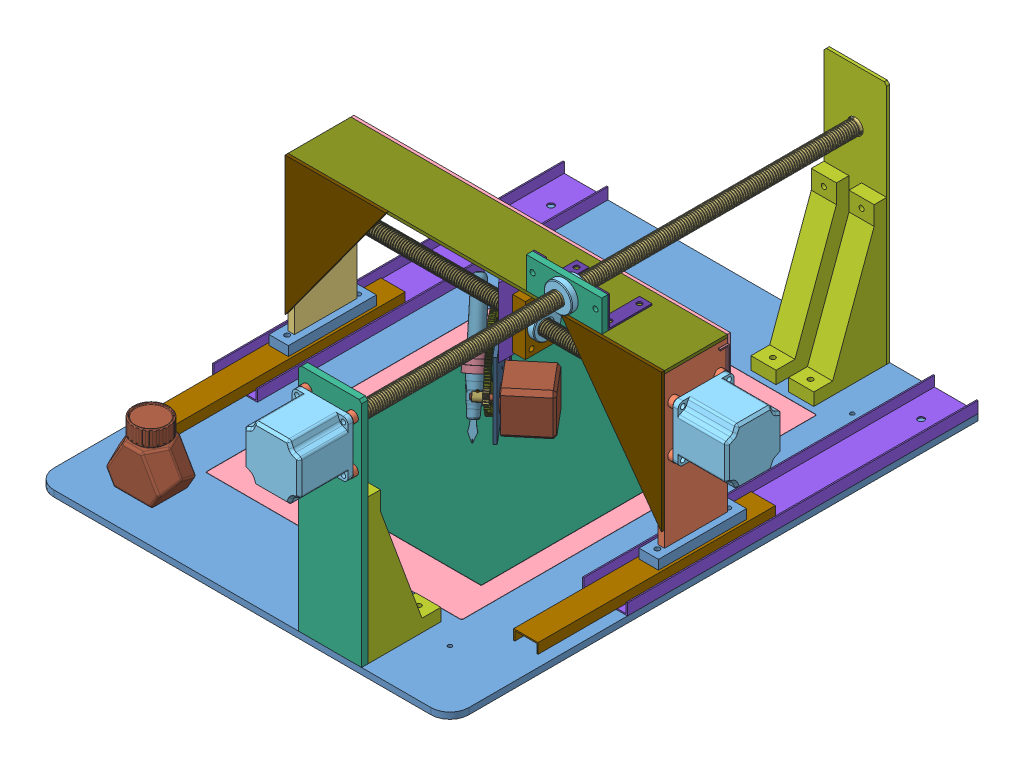
SolidWorks assembly Herald, configuration Default. Lengths in mm.
Overall size (459.08 262.99 592.84).
56 component instances, 36 part files, 131 mates.
Components (placement in the parent):
- Base-2: Base [Default] at (-178.3326 42.4149 224.7348) size (419.1 6.35 533.4)
- Stepper spacer-1: Stepper spacer [Default] at (96.4904 264.5125 229.8148) x (1 0 0) z (0 1 0) size (10.16 5.08 10.16)
- Stepper spacer-2: Stepper spacer [Default] at (143.2264 217.7765 229.8148) x (1 0 0) z (0 1 0) size (10.16 5.08 10.16)
- Stepper spacer-3: Stepper spacer [Default] at (143.2264 264.5125 229.8148) x (-0.279349 0.96019 0) z (-0.96019 -0.279349 0) size (10.16 5.08 10.16)
- Stepper spacer-6: Stepper spacer [Default] at (96.4904 217.7765 229.8148) x (1 0 0) z (0 1 0) size (10.16 5.08 10.16)
- Y axis threaded rod-1: Y axis threaded rod [Default] at (119.8584 241.1445 209.7488) x (0 0 -1) z (0.590642 -0.806934 0) size (518.41 15.92 15.92)
- Glass pane-3: Glass pane [Default] at (-98.1639 45.5649 -226.1152) x (0 0 1) z (-1 0 0) size (358.78 3.2 258.76)
- stepper motor_vexta PK266MA-2: stepper motor_vexta PK266MA [Default] at (226.391 199.6155 -15.0171) x (0 0 -1) z (1 0 0) size (56.39 56.39 74.42)
- Stepper spacer-7: Stepper spacer [Default] at (226.391 194.7895 -66.5791) x (0 1 0) z (0 0 1) size (10.16 5.08 10.16)
- Stepper spacer-8: Stepper spacer [Default] at (226.391 148.0535 -66.5791) x (0 1 0) z (0 0 1) size (10.16 5.08 10.16)
- Stepper spacer-9: Stepper spacer [Default] at (226.391 194.7895 -19.8431) x (0 1 0) z (0 0 1) size (10.16 5.08 10.16)
- Stepper spacer-10: Stepper spacer [Default] at (226.391 148.0535 -19.8431) x (0 1 0) z (0 0 1) size (10.16 5.08 10.16)
- Y axis stepper wall-3: Y axis stepper wall [Default] at (151.6084 48.7649 224.7348) x (-1 0 0) z (0 0 -1) size (63.5 233.27 6.35)
- Y axis stepper wall opposite-1: Y axis stepper wall opposite [Default] at (88.1084 48.7649 -308.6652) size (63.5 245.97 3.05)
- sldier_base-8: sldier_base [Default] at (-133.0698 60.2965 45.3473) x (-1 0 0) z (0 0 -1) size (45.26 11.53 354.01)
- slider_top-8: slider_top [Default] at (-143.3949 50.0349 125.3814) x (-1 0 0) z (0 0 -1) size (24.61 10.26 239.71)
- sldier_base-9: sldier_base [Default] at (240.7674 60.2965 45.3473) x (-1 0 0) z (0 0 -1) size (45.26 11.53 354.01)
- slider_top-9: slider_top [Default] at (230.4423 50.0349 125.3814) x (-1 0 0) z (0 0 -1) size (24.61 10.26 239.71)
- Rubber foot new-1: Rubber foot new [Default] at (177.2674 42.4149 -245.1652) x (-0.837169 0 -0.546944) z (-0.546944 0 0.837169) size (24.77 10.67 24.77)
- Rubber foot new-2: Rubber foot new [Default] at (-114.8326 42.4149 161.2348) x (-0.837169 0 -0.546944) z (-0.546944 0 0.837169) size (24.77 10.67 24.77)
- Rubber foot new-3: Rubber foot new [Default] at (177.2674 42.4149 161.2348) x (-0.837169 0 -0.546944) z (-0.546944 0 0.837169) size (24.77 10.67 24.77)
- Rubber foot new-4: Rubber foot new [Default] at (-114.8326 42.4149 -245.1652) x (-0.837169 0 -0.546944) z (-0.546944 0 0.837169) size (24.77 10.67 24.77)
- Ink bottle-1: Ink bottle [Default] at (-144.1882 48.7649 154.4245) size (62.44 62.79 38.1)
- X axis threaded rod-1: X axis threaded rod [Default] at (-155.5742 171.4215 -43.2111) x (1 0 0) z (0 0.602009 0.798489) size (361.9 15.92 15.92)
- x_sldier_base-1: x_sldier_base [Default] at (223.3049 217.4717 -65.9695) x (0 -1 0) z (-1 0 0) size (35.2 8.99 384.18)
- x_slider_top-1: x_slider_top [Default] at (59.6982 212.0107 -73.6911) x (0 -1 0) z (-1 0 0) size (24.28 7.29 231.78)
- Paper sheet-1: Paper sheet [Default] at (-75.6268 48.7649 92.6403) size (215.9 0.25 279.4)
- Recognizer top-1: Recognizer top [Default] at (221.311 225.2695 -11.4611) x (-1 0 0) z (0 -1 0) size (380.19 63.5 3.05)
- Recognizer top bracket-1: Recognizer top bracket [Default] at (157.9584 225.2695 -62.2611) x (0 0 1) z (-1 0 0) size (44.45 31.75 12.7)
- Recognizer top bracket-2: Recognizer top bracket [Default] at (94.4584 225.2695 -62.2611) x (0 0 1) z (-1 0 0) size (44.45 31.75 12.7)
- Recognizer bracket-1: Recognizer bracket [Default] at (-158.8762 85.5695 -11.4611) size (101.6 139.7 3.05)
- Recognizer bracket-2: Recognizer bracket [Default] at (221.311 85.5695 -8.4131) x (-1 0 0) z (0 0 -1) size (101.6 139.7 3.05)
- Recognizer foot-1: Recognizer foot [Default] at (-145.8968 60.2965 -87.6611) x (-1 0 0) z (0 0 -1) size (19.61 9.53 88.9)
- Recognizer foot-2: Recognizer foot [Default] at (227.9404 60.2965 -87.6611) x (-1 0 0) z (0 0 -1) size (19.61 9.53 88.9)
- Recognizer stepper arm-1: Recognizer stepper arm [Default] at (214.961 63.3445 -11.4611) x (0 0 -1) z (1 0 0) size (63.5 158.88 6.35)
- Recognizer regular arm-1: Recognizer regular arm [Default] at (-152.5262 63.3445 -74.9611) x (0 0 1) z (-1 0 0) size (63.5 158.88 6.35)
- Recognizer back plate-1: Recognizer back plate [Default] at (221.311 174.4695 -74.9611) x (-1 0 0) z (0 0 -1) size (380.19 50.8 3.05)
- ACME nut fast travel-1: ACME nut fast travel [Default] at (119.8584 241.1445 -5.1111) x (-1 0 0) z (0 -1 0) size (28.45 19.05 28.45)
- Recognizer nut plate-1: Recognizer nut plate [Default] at (157.9584 225.2695 -11.4611) x (-1 0 0) z (0 0 -1) size (76.2 31.75 6.35)
- Gusset-1: Gusset [Default] at (88.1084 48.7649 218.3848) size (25.4 146.05 73.66)
- Gusset-2: Gusset [Default] at (151.6084 48.7649 -305.6172) x (-1 0 0) z (0 0 -1) size (25.4 146.05 73.66)
- Gusset-4: Gusset [Default] at (126.2084 48.7649 218.3848) size (25.4 146.05 73.66)
- Gusset-5: Gusset [Default] at (113.5084 48.7649 -305.6172) x (-1 0 0) z (0 0 -1) size (25.4 146.05 73.66)
- stepper motor_vexta PK266MA-3: stepper motor_vexta PK266MA [Default] at (91.6644 269.3385 229.8148) size (56.39 56.39 74.42)
- L shape-3: L shape [Default] at (49.5883 143.9895 -15.6013) x (0 0 -1) z (1 0 0) size (50.8 69.85 42.63)
- Print head nut plate-2: Print head nut plate [Default] at (49.5883 171.4215 -46.4369) x (0 0 -1) z (1 0 0) size (33.02 50.8 12.7)
- ACME nut fast travel-3: ACME nut fast travel [Default] at (68.6383 171.4215 -46.4369) x (0 -0.167452 -0.98588) z (0 0.98588 -0.167452) size (28.45 19.05 28.45)
- Mechanical plate-2: Mechanical plate [Default] at (54.4149 80.4895 -4.9098) x (-0.642788 0 -0.766044) z (0.766044 0 -0.642788) size (88.9 76.2 3.17)
- Stepper Pololu-4: Stepper Pololu [Default] at (85.9354 124.2245 -37.6249) x (-0.642788 0 -0.766044) z (0 1 0) size (42.3 64 42.3)
- Gear small-2: Gear small [Default] at (32.4517 103.0745 -20.3561) x (-0.766044 0 0.642788) z (0.619672 0.265763 0.738496) size (12.72 12.73 12.52)
- P clamp-3: P clamp [Default] at (-11.0372 89.3708 -70.3427) x (-0.549529 -0.518768 -0.654903) z (-0.333457 0.854915 -0.397399) size (35.56 20.32 16.76)
- Pen-3: Pen [Default] at (-22.3687 147.4305 -68.0409) x (-0.333457 0.854915 -0.397399) z (-0.549529 -0.518768 -0.654903) size (122.97 14 14)
- Spacer large-1: Spacer large [Default] at (9.6686 103.0745 -58.2363) x (-0.492404 0.642788 -0.586824) z (0.413176 0.766044 0.492404) size (27.94 5.71 27.94)
- Gear large-2: Gear large [Default] at (4.3859 103.0745 -53.8036) x (0.766044 0 -0.642788) z (-0.549529 -0.518768 -0.654903) size (12.71 77.81 77.81)
- Gear back plate-1: Gear back plate [Default] at (14.6303 103.0745 -62.3997) x (0.549529 0.518768 0.654903) z (0.333457 -0.854915 0.397399) size (22.86 3.05 22.86)
- Set screw-1: Set screw [Default] at (26.7072 107.9333 -17.2844) x (0.383542 -0.125263 -0.914989) z (0.170829 -0.964039 0.203586) size (2.54 2.54 2.54)
Mates (geometry in assembly coordinates):
- Coincident59: coincident anti-aligned: plane of Base-2 through (-98.1639 45.5649 -226.1152) normal (1 0 0); plane of Glass pane-3 through (-98.1639 48.7649 131.5098) normal (-1 0 0)
- Coincident60: coincident anti-aligned: plane of Base-2 through (-98.1639 45.5649 132.6598) normal (0 0 -1); plane of Glass pane-3 through (159.4486 48.7649 132.6598) normal (0 0 1)
- Coincident61: coincident aligned: plane of Base-2 through (-178.3326 48.7649 224.7348) normal (0 1 0); plane of Glass pane-3 through (-98.1639 48.7649 -226.1152) normal (0 1 0)
- Concentric86: concentric anti-aligned: circle of stepper motor_vexta PK266MA-2; circle of Stepper spacer-7
- Concentric87: concentric anti-aligned: circle of stepper motor_vexta PK266MA-2; circle of Stepper spacer-10
- Coincident128: coincident anti-aligned: plane of stepper motor_vexta PK266MA-2 through (226.391 199.6155 -15.0171) normal (-1 0 0); plane of Stepper spacer-7 through (226.391 194.7895 -66.5791) normal (1 0 0)
- Concentric97: concentric aligned: circle of Stepper spacer-1; circle of Y axis stepper wall-3
- Concentric98: concentric aligned: circle of Stepper spacer-3; circle of Y axis stepper wall-3
- Concentric99: concentric aligned: circle of Stepper spacer-6; circle of Y axis stepper wall-3
- Concentric100: concentric aligned: circle of Stepper spacer-2; circle of Y axis stepper wall-3
- Coincident138: coincident anti-aligned: plane of Stepper spacer-2 through (143.2264 217.7765 224.7348) normal (0 0 -1); plane of Y axis stepper wall-3 through (151.6084 48.7649 224.7348) normal (0 0 1)
- Coincident139: coincident anti-aligned: plane of Stepper spacer-6 through (96.4904 217.7765 224.7348) normal (0 0 -1); plane of Y axis stepper wall-3 through (151.6084 48.7649 224.7348) normal (0 0 1)
- Coincident140: coincident anti-aligned: plane of Stepper spacer-3 through (143.2264 264.5125 224.7348) normal (0 0 -1); plane of Y axis stepper wall-3 through (151.6084 48.7649 224.7348) normal (0 0 1)
- Coincident141: coincident anti-aligned: plane of Stepper spacer-1 through (96.4904 264.5125 224.7348) normal (0 0 -1); plane of Y axis stepper wall-3 through (151.6084 48.7649 224.7348) normal (0 0 1)
- LimitDistance1: limit distance = 194.3341 mm aligned: plane of slider_top-8 through (-143.3949 50.0349 -114.3311) normal (0 0 -1); plane of sldier_base-8 through (-133.0698 60.2965 -308.6652) normal (0 0 -1)
- Coincident3: coincident aligned: plane of sldier_base-8 through (-155.7012 60.2965 45.3473) normal (-1 0 0); plane of slider_top-8 through (-155.7012 50.0349 125.3814) normal (-1 0 0)
- Coincident4: coincident anti-aligned: plane of sldier_base-8 through (-177.0626 50.0349 -308.6652) normal (0 1 0); plane of slider_top-8 through (-144.6649 50.0349 -114.3311) normal (0 -1 0)
- Coincident145: coincident anti-aligned: plane of Base-2 through (-178.3326 48.7649 224.7348) normal (0 1 0); plane of sldier_base-8 through (-133.0698 48.7649 -308.6652) normal (0 -1 0)
- Coincident147: coincident anti-aligned: plane of Base-2 through (-178.3326 42.4149 224.7348) normal (0 -1 0); plane of Rubber foot new-1 through (175.1941 42.4149 -246.5197) normal (0 1 0)
- Coincident148: coincident anti-aligned: plane of Base-2 through (-178.3326 42.4149 224.7348) normal (0 -1 0); plane of Rubber foot new-2 through (-116.9059 42.4149 159.8803) normal (0 1 0)
- Coincident149: coincident anti-aligned: plane of Base-2 through (-178.3326 42.4149 224.7348) normal (0 -1 0); plane of Rubber foot new-3 through (175.1941 42.4149 159.8803) normal (0 1 0)
- Coincident150: coincident anti-aligned: plane of Base-2 through (-178.3326 42.4149 224.7348) normal (0 -1 0); plane of Rubber foot new-4 through (-116.9059 42.4149 -246.5197) normal (0 1 0)
- Coincident151: coincident anti-aligned: plane of Base-2 through (-178.3326 48.7649 224.7348) normal (0 1 0); plane of Ink bottle-1 through (-93.3882 48.7649 192.5245) normal (0 -1 0)
- Coincident152: coincident anti-aligned: plane of stepper motor_vexta PK266MA-2 through (206.325 171.4215 -43.2111) normal (-1 0 0); plane of X axis threaded rod-1 through (206.325 171.4215 -43.2111) normal (1 0 0)
- Coincident155: coincident anti-aligned: plane of x_sldier_base-1 through (-160.8701 183.5373 -73.6911) normal (0 0 1); plane of x_slider_top-1 through (-172.0768 187.7283 -73.6911) normal (0 0 -1)
- Coincident156: coincident aligned: plane of x_sldier_base-1; plane of x_slider_top-1
- Coincident165: coincident anti-aligned: plane of Base-2 through (-178.3326 48.7649 224.7348) normal (0 1 0); plane of Paper sheet-1 through (-75.6268 48.7649 92.6403) normal (0 -1 0)
- LimitDistance2: limit distance = 163.6067 mm aligned: plane of x_slider_top-1 through (59.6982 212.0107 -73.6911) normal (1 0 0); plane of x_sldier_base-1 through (223.3049 217.4717 -65.9695) normal (1 0 0)
- Concentric145: concentric anti-aligned: circle of stepper motor_vexta PK266MA-2; circle of X axis threaded rod-1
- Coincident203: coincident aligned: plane of Base-2 through (-178.3326 48.7649 224.7348) normal (0 0 1); plane of Y axis stepper wall-3 through (151.6084 48.7649 224.7348) normal (0 0 1)
- Coincident204: coincident anti-aligned: plane of Base-2 through (-178.3326 48.7649 224.7348) normal (0 1 0); plane of Y axis stepper wall-3 through (151.6084 48.7649 218.3848) normal (0 -1 0)
- Coincident210: coincident aligned: plane of Base-2 through (-178.3326 48.7649 -308.6652) normal (0 0 -1); plane of Y axis stepper wall opposite-1 through (88.1084 48.7649 -308.6652) normal (0 0 -1)
- Coincident211: coincident anti-aligned: plane of Base-2 through (-178.3326 48.7649 224.7348) normal (0 1 0); plane of Y axis stepper wall opposite-1 through (88.1084 48.7649 -305.6172) normal (0 -1 0)
- Concentric172: concentric anti-aligned: circle of Y axis threaded rod-1; circle of Y axis stepper wall opposite-1
- Coincident7: coincident anti-aligned: plane of Recognizer top-1 through (221.311 225.2695 -11.4611) normal (0 1 0); plane of Recognizer top bracket-1 through (145.2584 225.2695 -62.2611) normal (0 -1 0)
- Coincident14: coincident anti-aligned: plane of Recognizer top-1 through (221.311 225.2695 -11.4611) normal (0 1 0); plane of Recognizer top bracket-2 through (81.7584 225.2695 -62.2611) normal (0 -1 0)
- Coincident26: coincident aligned: plane of Recognizer top-1 through (221.311 225.2695 -11.4611) normal (0 1 0); plane of Recognizer bracket-1 through (-158.8762 225.2695 -8.4131) normal (0 1 0)
- Coincident27: coincident anti-aligned: plane of Recognizer top-1 through (221.311 222.2215 -11.4611) normal (0 0 1); plane of Recognizer bracket-2 through (221.311 85.5695 -11.4611) normal (0 0 -1)
- Coincident29: coincident aligned: plane of Recognizer top-1 through (221.311 225.2695 -11.4611) normal (0 1 0); plane of Recognizer bracket-2 through (221.311 225.2695 -11.4611) normal (0 1 0)
- Coincident56: coincident anti-aligned: plane of Recognizer top-1 through (221.311 222.2215 -11.4611) normal (0 0 1); plane of Recognizer bracket-1 through (-158.8762 85.5695 -11.4611) normal (0 0 -1)
- Coincident57: coincident aligned: plane of Recognizer top-1 through (221.311 222.2215 -11.4611) normal (1 0 0); plane of Recognizer stepper arm-1 through (221.311 63.3445 -11.4611) normal (1 0 0)
- Coincident58: coincident anti-aligned: plane of Recognizer top-1 through (221.311 222.2215 -11.4611) normal (0 -1 0); plane of Recognizer stepper arm-1 through (221.311 222.2215 -11.4611) normal (0 1 0)
- Coincident215: coincident aligned: plane of Recognizer top-1 through (-158.8762 222.2215 -11.4611) normal (-1 0 0); plane of Recognizer regular arm-1 through (-158.8762 63.3445 -74.9611) normal (-1 0 0)
- Coincident63: coincident aligned: plane of Recognizer top-1 through (221.311 225.2695 -11.4611) normal (0 1 0); plane of Recognizer back plate-1 through (221.311 225.2695 -78.0091) normal (0 1 0)
- Coincident64: coincident anti-aligned: plane of Recognizer top-1 through (221.311 222.2215 -74.9611) normal (0 0 -1); plane of Recognizer back plate-1 through (221.311 174.4695 -74.9611) normal (0 0 1)
- Coincident65: coincident anti-aligned: plane of Recognizer top-1 through (221.311 222.2215 -11.4611) normal (0 -1 0); plane of Recognizer regular arm-1 through (-158.8762 222.2215 -74.9611) normal (0 1 0)
- Coincident80: coincident aligned: plane of Recognizer top-1 through (221.311 222.2215 -11.4611) normal (0 0 1); plane of Recognizer nut plate-1 through (157.9584 225.2695 -11.4611) normal (0 0 1)
- Concentric19: concentric aligned: circle of Recognizer top bracket-1; circle of Recognizer nut plate-1
- Coincident75: coincident anti-aligned: plane of Recognizer top bracket-1 through (145.2584 225.2695 -17.8111) normal (0 0 1); plane of Recognizer nut plate-1 through (157.9584 225.2695 -17.8111) normal (0 0 -1)
- Concentric18: concentric aligned: circle of Recognizer top bracket-2; circle of Recognizer nut plate-1
- Concentric21: concentric aligned: circle of Recognizer top bracket-2; circle of Recognizer nut plate-1
- Coincident78: coincident anti-aligned: plane of Recognizer top bracket-2 through (81.7584 225.2695 -17.8111) normal (0 0 1); plane of Recognizer nut plate-1 through (157.9584 225.2695 -17.8111) normal (0 0 -1)
- Coincident51: coincident aligned: plane of Recognizer bracket-1 through (-158.8762 85.5695 -8.4131) normal (-1 0 0); plane of Recognizer regular arm-1 through (-158.8762 63.3445 -74.9611) normal (-1 0 0)
- Coincident52: coincident anti-aligned: plane of Recognizer bracket-1 through (-158.8762 85.5695 -11.4611) normal (0 0 -1); plane of Recognizer regular arm-1 through (-158.8762 63.3445 -11.4611) normal (0 0 1)
- Coincident40: coincident anti-aligned: plane of Recognizer bracket-2 through (221.311 85.5695 -11.4611) normal (0 0 -1); plane of Recognizer stepper arm-1 through (221.311 63.3445 -11.4611) normal (0 0 1)
- Coincident216: coincident aligned: plane of Recognizer bracket-2 through (221.311 85.5695 -11.4611) normal (1 0 0); plane of Recognizer stepper arm-1 through (221.311 63.3445 -11.4611) normal (1 0 0)
- Coincident69: coincident anti-aligned: plane of Recognizer foot-1 through (-158.8762 63.3445 -12.7311) normal (1 0 0); plane of Recognizer regular arm-1 through (-158.8762 63.3445 -74.9611) normal (-1 0 0)
- Coincident68: coincident anti-aligned: plane of Recognizer foot-2 through (221.311 63.3445 -12.7311) normal (-1 0 0); plane of Recognizer stepper arm-1 through (221.311 63.3445 -11.4611) normal (1 0 0)
- Coincident62: coincident aligned: plane of Recognizer stepper arm-1 through (221.311 63.3445 -11.4611) normal (1 0 0); plane of Recognizer back plate-1 through (221.311 174.4695 -78.0091) normal (1 0 0)
- Concentric20: concentric anti-aligned: cylinder of ACME nut fast travel-1 through (119.8584 241.1445 -5.1111) axis (0 0 -1) radius 11.8999; cylinder of Recognizer nut plate-1 through (119.8584 241.1445 -17.8111) axis (0 0 1) radius 11.8999
- Coincident76: coincident anti-aligned: plane of ACME nut fast travel-1 through (105.6344 241.1445 -11.4611) normal (0 0 -1); plane of Recognizer nut plate-1 through (157.9584 225.2695 -11.4611) normal (0 0 1)
- Coincident217: coincident anti-aligned: plane of Recognizer foot-1 through (-145.8968 60.2965 -87.6611) normal (0 -1 0); plane of slider_top-8 through (-143.3949 60.2965 -114.3311) normal (0 1 0)
- Coincident218: coincident anti-aligned: plane of Recognizer stepper arm-1 through (221.311 63.3445 -11.4611) normal (1 0 0); plane of Stepper spacer-7 through (221.311 194.7895 -66.5791) normal (-1 0 0)
- Coincident219: coincident anti-aligned: plane of Recognizer stepper arm-1 through (221.311 63.3445 -11.4611) normal (1 0 0); plane of Stepper spacer-10 through (221.311 148.0535 -19.8431) normal (-1 0 0)
- Coincident220: coincident anti-aligned: plane of Recognizer stepper arm-1 through (221.311 63.3445 -11.4611) normal (1 0 0); plane of Stepper spacer-8 through (221.311 148.0535 -66.5791) normal (-1 0 0)
- Coincident221: coincident anti-aligned: plane of Recognizer stepper arm-1 through (221.311 63.3445 -11.4611) normal (1 0 0); plane of Stepper spacer-9 through (221.311 194.7895 -19.8431) normal (-1 0 0)
- Concentric176: concentric anti-aligned: circle of Recognizer stepper arm-1; circle of Stepper spacer-10
- Concentric177: concentric anti-aligned: circle of Recognizer stepper arm-1; circle of Stepper spacer-8
- Concentric178: concentric anti-aligned: circle of Recognizer stepper arm-1; circle of Stepper spacer-9
- Concentric179: concentric anti-aligned: circle of Recognizer stepper arm-1; circle of Stepper spacer-7
- Coincident222: coincident anti-aligned: plane of Recognizer back plate-1 through (221.311 174.4695 -74.9611) normal (0 0 1); plane of x_sldier_base-1 through (-160.8701 217.4717 -74.9611) normal (0 0 -1)
- Concentric180: concentric aligned: circle of Recognizer back plate-1; circle of x_sldier_base-1
- Concentric181: concentric aligned: circle of Recognizer back plate-1; circle of x_sldier_base-1
- Coincident223: coincident anti-aligned: plane of Y axis stepper wall-3 through (151.6084 48.7649 218.3848) normal (0 0 -1); plane of Gusset-4 through (151.6084 48.7649 218.3848) normal (0 0 1)
- Coincident224: coincident aligned: plane of Y axis stepper wall-3 through (151.6084 48.7649 218.3848) normal (1 0 0); plane of Gusset-4 through (151.6084 48.7649 218.3848) normal (1 0 0)
- Coincident225: coincident anti-aligned: plane of Base-2 through (-178.3326 48.7649 224.7348) normal (0 1 0); plane of Gusset-4 through (151.6084 48.7649 144.7248) normal (0 -1 0)
- Coincident229: coincident anti-aligned: plane of Base-2 through (-178.3326 48.7649 224.7348) normal (0 1 0); plane of Gusset-1 through (113.5084 48.7649 144.7248) normal (0 -1 0)
- Coincident230: coincident anti-aligned: plane of Y axis stepper wall-3 through (151.6084 48.7649 218.3848) normal (0 0 -1); plane of Gusset-1 through (113.5084 48.7649 218.3848) normal (0 0 1)
- Coincident231: coincident aligned: plane of Y axis stepper wall-3 through (88.1084 48.7649 218.3848) normal (-1 0 0); plane of Gusset-1 through (88.1084 48.7649 218.3848) normal (-1 0 0)
- Coincident232: coincident anti-aligned: plane of Y axis stepper wall opposite-1 through (88.1084 48.7649 -305.6172) normal (0 0 1); plane of Gusset-5 through (88.1084 48.7649 -305.6172) normal (0 0 -1)
- Coincident233: coincident anti-aligned: plane of Base-2 through (-178.3326 48.7649 224.7348) normal (0 1 0); plane of Gusset-5 through (88.1084 48.7649 -231.9572) normal (0 -1 0)
- Coincident234: coincident aligned: plane of Y axis stepper wall opposite-1 through (88.1084 48.7649 -305.6172) normal (-1 0 0); plane of Gusset-5 through (88.1084 48.7649 -305.6172) normal (-1 0 0)
- Coincident235: coincident anti-aligned: plane of Base-2 through (-178.3326 48.7649 224.7348) normal (0 1 0); plane of Gusset-2 through (126.2084 48.7649 -231.9572) normal (0 -1 0)
- Coincident236: coincident anti-aligned: plane of Y axis stepper wall opposite-1 through (88.1084 48.7649 -305.6172) normal (0 0 1); plane of Gusset-2 through (126.2084 48.7649 -305.6172) normal (0 0 -1)
- Coincident237: coincident aligned: plane of Y axis stepper wall opposite-1 through (151.6084 48.7649 -305.6172) normal (1 0 0); plane of Gusset-2 through (151.6084 48.7649 -305.6172) normal (1 0 0)
- Concentric183: concentric aligned: circle of slider_top-8; circle of Recognizer foot-1
- Coincident239: coincident anti-aligned: plane of Recognizer foot-2 through (227.9404 63.3445 -87.6611) normal (0 1 0); plane of Recognizer stepper arm-1 through (221.311 63.3445 -11.4611) normal (0 -1 0)
- Coincident240: coincident anti-aligned: plane of slider_top-9 through (230.4423 60.2965 -114.3311) normal (0 1 0); plane of Recognizer foot-2 through (227.9404 60.2965 -87.6611) normal (0 -1 0)
- Concentric184: concentric aligned: circle of slider_top-9; circle of Recognizer foot-2
- Coincident241: coincident anti-aligned: plane of Stepper spacer-2 through (143.2264 217.7765 229.8148) normal (0 0 1); plane of stepper motor_vexta PK266MA-3 through (91.6644 269.3385 229.8148) normal (0 0 -1)
- Concentric185: concentric anti-aligned: circle of Y axis stepper wall-3; circle of stepper motor_vexta PK266MA-3
- Concentric186: concentric aligned: circle of Stepper spacer-1; circle of stepper motor_vexta PK266MA-3
- Concentric187: concentric aligned: circle of Y axis threaded rod-1; circle of stepper motor_vexta PK266MA-3
- Concentric189: concentric anti-aligned: cylinder of Y axis threaded rod-1 through (119.8584 241.1445 -308.6652) axis (0 0 1) radius 6.35; cylinder of ACME nut fast travel-1 through (119.8584 241.1445 -5.1111) axis (0 0 -1) radius 14.224
- Coincident242: coincident anti-aligned: plane of Recognizer foot-2 through (221.311 63.3445 -12.7311) normal (0 0 -1); plane of Recognizer stepper arm-1 through (214.961 63.3445 -12.7311) normal (0 0 1)
- Concentric190: concentric anti-aligned: circle of Base-2; circle of Rubber foot new-2
- Concentric191: concentric anti-aligned: circle of Base-2; circle of Rubber foot new-3
- Concentric192: concentric aligned: cylinder of Base-2 through (177.2674 48.7649 -245.1652) axis (0 1 0) radius 2.0193; circle of Rubber foot new-1
- Concentric193: concentric anti-aligned: circle of Base-2; circle of Rubber foot new-4
- Coincident243: coincident aligned: plane of Base-2 through (-178.3326 48.7649 -308.6652) normal (0 0 -1); plane of sldier_base-8 through (-133.0698 60.2965 -308.6652) normal (0 0 -1)
- Concentric1: concentric aligned: cylinder of L shape-3 through (49.5883 190.4715 -36.2769) axis (-1 0 0) radius 2.3559; cylinder of Print head nut plate-2 through (62.2883 190.4715 -36.2769) axis (-1 0 0) radius 2.54
- Concentric2: concentric aligned: cylinder of L shape-3 through (49.5883 190.4715 -56.5969) axis (-1 0 0) radius 2.3559; cylinder of Print head nut plate-2 through (62.2883 190.4715 -56.5969) axis (-1 0 0) radius 2.54
- Concentric3: concentric: cylinder of Print head nut plate-2 through (62.2883 171.4215 -46.4369) axis (-1 0 0) radius 11.8999; cylinder of ACME nut fast travel-3 through (16.413 171.4215 -46.4369) axis (-1 0 0) radius 11.8999
- Concentric4: concentric aligned: circle of Mechanical plate-2; circle of Stepper Pololu-4
- Concentric5: concentric aligned: cylinder of Mechanical plate-2 through (30.1937 87.5595 -38.7149) axis (-0.766044 0 0.642788) radius 1.4605; cylinder of Stepper Pololu-4 through (35.556 87.5595 -43.2144) axis (-0.766044 0 0.642788) radius 1.5
- Coincident245: coincident anti-aligned: plane of Mechanical plate-2 through (56.8471 80.4895 -6.9506) normal (0.766044 0 -0.642788); plane of Stepper Pololu-4 through (33.0959 103.0745 -35.2562) normal (-0.766044 0 0.642788)
- Coincident19: coincident anti-aligned: plane of Mechanical plate-2 through (54.4149 80.4895 -4.9098) normal (-0.766044 0 0.642788); plane of Spacer large-1 through (9.6686 103.0745 -58.2363) normal (0.766044 0 -0.642788)
- Concentric13: concentric anti-aligned: cylinder of Mechanical plate-2 through (12.1008 103.0745 -60.2772) axis (-0.766044 0 0.642788) radius 10.3124; cylinder of Spacer large-1 through (5.2926 103.0745 -54.5644) axis (0.766044 0 -0.642788) radius 10.3124
- Concentric7: concentric aligned: circle of Stepper Pololu-4; circle of Gear small-2
- Tangent1: tangent anti-aligned: cylinder of Stepper Pololu-4 through (23.3136 103.0745 -12.6883) axis (-0.766044 0 0.642788) radius 2.5; plane of Set screw-1 through (27.1411 105.4846 -16.7673) normal (0.170829 -0.964039 0.203586)
- GearMate2: gear = 12.3031 : 77.3906 mm: circle of Gear large-2; circle of Gear small-2
- Concentric196: concentric anti-aligned: cylinder of Gear small-2 through (26.4811 109.2093 -17.5539) axis (0.170829 -0.964039 0.203586) radius 1.27; cylinder of Set screw-1 through (27.1411 105.4846 -16.7673) axis (-0.170829 0.964039 -0.203586) radius 1.27
- Concentric12: concentric anti-aligned: circle of P clamp-3; circle of Pen-3
- Coincident18: coincident aligned: plane of P clamp-3 through (-11.0372 89.3708 -70.3427) normal (-0.333457 0.854915 -0.397399); plane of Pen-3
- Parallel2: parallel anti-aligned: plane of P clamp-3; plane of Pen-3 through (17.7323 52.8421 -25.96) normal (0.549529 0.518768 0.654903)
- Coincident24: coincident aligned: circle of P clamp-3; circle of Gear large-2
- Concentric15: concentric aligned: cylinder of P clamp-3 through (-3.4999 96.4862 -61.36) axis (-0.766044 0 0.642788) radius 1.27; cylinder of Gear large-2 through (5.3163 96.4862 -68.7577) axis (-0.766044 0 0.642788) radius 1.27
- Concentric14: concentric anti-aligned: cylinder of Spacer large-1 through (5.2926 103.0745 -54.5644) axis (0.766044 0 -0.642788) radius 13.97; circle of Gear large-2
- Coincident23: coincident anti-aligned: plane of Spacer large-1 through (5.2926 103.0745 -54.5644) normal (-0.766044 0 0.642788); plane of Gear large-2 through (5.2926 103.0745 -54.5644) normal (0.766044 0 -0.642788)
- Coincident247: coincident anti-aligned: cylinder of Gear large-2 through (7.969 109.178 -61.6449) axis (0.766044 0 -0.642788) radius 1.27; circle of Gear back plate-1
- Concentric17: concentric aligned: cylinder of Gear large-2 through (12.7303 96.971 -55.9706) axis (0.766044 0 -0.642788) radius 1.27; cylinder of Gear back plate-1 through (14.676 96.971 -57.6033) axis (0.766044 0 -0.642788) radius 1.27
- Coincident248: coincident anti-aligned: plane of Gear large-2 through (12.2954 103.0745 -60.4404) normal (0.766044 0 -0.642788); plane of Gear back plate-1 through (12.2954 103.0745 -60.4404) normal (-0.766044 0 0.642788)
- Concentric197: concentric aligned: cylinder of x_slider_top-1 through (15.2482 207.4895 -73.6911) axis (0 0 1) radius 2.54; cylinder of L shape-3 through (15.2482 207.4895 -66.4013) axis (0 0 1) radius 2.0193
- Concentric198: concentric aligned: cylinder of x_slider_top-1 through (40.6482 207.4895 -73.6911) axis (0 0 1) radius 2.54; cylinder of L shape-3 through (40.6482 207.4895 -66.4013) axis (0 0 1) radius 2.0193
- Coincident249: coincident anti-aligned: plane of x_slider_top-1 through (-172.0768 212.0107 -66.4013) normal (0 0 1); plane of L shape-3 through (49.5883 213.8395 -66.4013) normal (0 0 -1)
- Coincident250: coincident anti-aligned: plane of L shape-3 through (45.5243 213.8395 -20.4446) normal (-0.766044 0 0.642788); plane of Mechanical plate-2 through (56.8471 80.4895 -6.9506) normal (0.766044 0 -0.642788)
- Coincident251: coincident aligned: plane of L shape-3 through (28.2752 143.9895 -41.0013) normal (-0.642788 0 -0.766044); plane of Mechanical plate-2 through (25.843 80.4895 -38.9605) normal (-0.642788 0 -0.766044)
- Coincident252: coincident anti-aligned: plane of L shape-3; plane of Mechanical plate-2 through (56.8471 156.6895 -6.9506) normal (0 1 0)
- Coincident253: coincident anti-aligned: plane of L shape-3 through (49.5883 213.8395 -15.6013) normal (1 0 0); plane of Print head nut plate-2 through (49.5883 171.4215 -46.4369) normal (-1 0 0)
- Coincident255: coincident aligned: plane of Gear small-2 through (30.6324 103.0745 -18.8295) normal (-0.766044 0 0.642788); plane of Gear large-2 through (15.536 69.8237 -36.8207) normal (-0.766044 0 0.642788)
- Coincident256: coincident anti-aligned: plane of Print head nut plate-2 through (62.2883 171.4215 -46.4369) normal (1 0 0); plane of ACME nut fast travel-3 through (62.2883 169.0397 -60.4601) normal (-1 0 0)
